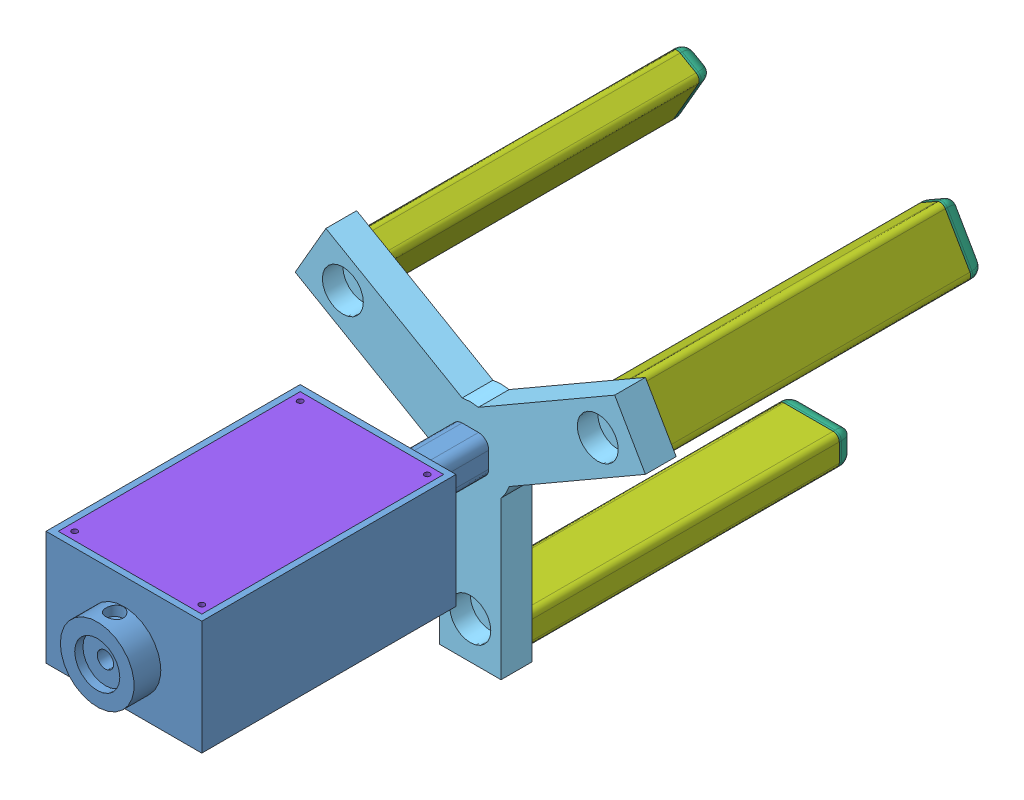
SolidWorks assembly NewGrapperWithServos, configuration Default. Lengths in mm.
Overall size (170.88 147.99 355).
26 component instances, 9 part files, 17 mates.
Components (placement in the parent):
- ServoHolder-1: ServoHolder [Default] at (20.6091 41.5283 66.4389) size (76 55.75 187)
- ServoWithHornCover-1: ServoWithHornCover [Default] at (-47.2507 32.9202 59.0729) x (0 0 -1) z (1 0 0) size (60.01 49.75 41.52) (flexible)
  - MG996R-1: MG996R [Default] at (22.884 11.6081 50.6098) size (53.5 42.75 19.5)
  - ServoHornWithGroove-1: ServoHornWithGroove [Default] at (12.384 56.3581 50.6098) x (0.653288 0 0.75711) z (0.75711 0 -0.653288) size (30 9.5 30)
  - ServoCover-1: ServoCover [Default] at (34.0772 41.3581 67.8598) x (-1 0 0) z (0 0 -1) size (57.5 20 34.5)
- ServoWithHornCover-2: ServoWithHornCover [Default] at (-12.7507 32.9202 59.0729) x (0 0 -1) z (1 0 0) size (60.01 49.75 41.52) (flexible)
  - MG996R-1: MG996R [Default] at (22.884 11.6081 50.6098) size (53.5 42.75 19.5)
  - ServoHornWithGroove-1: ServoHornWithGroove [Default] at (12.384 56.3581 50.6098) x (0.586538 0 0.809922) z (0.809922 0 -0.586538) size (30 9.5 30)
  - ServoCover-1: ServoCover [Default] at (34.0772 41.3581 67.8598) x (-1 0 0) z (0 0 -1) size (57.5 20 34.5)
- 3GripperAssembly-1: 3GripperAssembly [Default] at (-30.3334 -49.3942 19.9719) x (1 0 0) z (0 1 0) size (170.88 173 147.99)
  - EndEffector3Grapper-1: EndEffector3Grapper [Default] at (50.9425 60.533 115.9226) size (170.88 20 147.99)
  - FingerAssembly-1: FingerAssembly [Default] at (105.0348 198.5242 138.6511) x (-0.5 0 0.866025) z (0 1 0) size (30 15 158)
    - FingerTip-1: FingerTip [Default] at (7.3627 17.1904 24.0088) size (30 15 11)
    - Finger-1: Finger [Default] at (7.3627 18.2904 -122.9912) x (1 0 0) z (0 -1 0) size (30 150 15)
  - FingerAssembly-2: FingerAssembly [Default] at (4.2129 198.5242 151.4036) x (-0.5 0 -0.866025) z (0 1 0) size (30 15 158)
    - FingerTip-1: FingerTip [Default] at (7.3627 17.1904 24.0088) size (30 15 11)
    - Finger-1: Finger [Default] at (7.3627 18.2904 -122.9912) x (1 0 0) z (0 -1 0) size (30 150 15)
  - FingerAssembly-3: FingerAssembly [Default] at (43.5799 198.5242 57.713) x (1 0 0) z (0 1 0) size (30 15 158)
    - FingerTip-1: FingerTip [Default] at (7.3627 17.1904 24.0088) size (30 15 11)
    - Finger-1: Finger [Default] at (7.3627 18.2904 -122.9912) x (1 0 0) z (0 -1 0) size (30 150 15)
- ServoWithHornCover-4: ServoWithHornCover [Default] at (-30.0007 32.9202 119.5729) x (0 0 -1) z (1 0 0) size (60.01 49.75 41.52)
  - MG996R-1: MG996R [Default] at (22.884 11.6081 50.6098) size (53.5 42.75 19.5)
  - ServoHornWithGroove-1: ServoHornWithGroove [Default] at (12.384 56.3581 50.6098) x (-0.837169 0 -0.546944) z (-0.546944 0 0.837169) size (30 9.5 30)
  - ServoCover-1: ServoCover [Default] at (34.0772 41.3581 67.8598) x (-1 0 0) z (0 0 -1) size (57.5 20 34.5)
- ServoHolderCover-1: ServoHolderCover [Default] at (20.6091 94.2783 66.4389) x (0 0 -1) z (1 0 0) size (118 3 70)
- socket head cap screw_iso-1: socket head cap screw_iso [ISO 4762 M6 x 20 - 20S] at (20.6091 66.5283 -55.5611) x (0 0 1) z (-0.923728 -0.383049 0) size (26 10 10)
Mates (geometry in assembly coordinates):
- Coincident11: coincident anti-aligned: plane of ServoHolder-1 through (-6.3909 85.2783 15.9389) normal (1 0 0); plane of ServoWithHornCover-1/MG996R-1 through (-6.3909 80.2783 56.4389) normal (-1 0 0)
- Coincident13: coincident anti-aligned: plane of ServoWithHornCover-1/ServoCover-1 through (20.6091 74.2783 24.9957) normal (1 0 0); plane of ServoWithHornCover-2/ServoCover-1 through (20.6091 74.2783 24.9957) normal (-1 0 0)
- Coincident14: coincident aligned: plane of ServoWithHornCover-1/ServoCover-1 through (-13.8909 94.2783 58.4389) normal (0 1 0); plane of ServoWithHornCover-2/ServoCover-1 through (20.6091 94.2783 58.4389) normal (0 1 0)
- Coincident15: coincident aligned: plane of ServoWithHornCover-1/ServoCover-1 through (-13.8909 94.2783 13.9389) normal (0 0 -1); plane of ServoWithHornCover-2/ServoCover-1 through (20.6091 94.2783 13.9389) normal (0 0 -1)
- Coincident16: coincident anti-aligned: plane of ServoHolder-1 through (20.6091 44.5283 66.4389) normal (0 1 0); plane of ServoWithHornCover-1/MG996R-1 through (3.3591 44.5283 36.1889) normal (0 -1 0)
- Coincident17: coincident aligned: plane of ServoHolder-1 through (13.1091 85.2783 15.9389) normal (0 0 -1); plane of ServoWithHornCover-1/MG996R-1 through (13.1091 80.2783 15.9389) normal (0 0 -1)
- Coincident20: coincident anti-aligned: plane of ServoHolder-1 through (30.3591 85.2783 76.4389) normal (-1 0 0); plane of ServoWithHornCover-4/MG996R-1 through (30.3591 80.2783 116.9389) normal (1 0 0)
- Coincident21: coincident anti-aligned: plane of ServoHolder-1 through (20.6091 44.5283 66.4389) normal (0 1 0); plane of ServoWithHornCover-4/MG996R-1 through (20.6091 44.5283 96.6889) normal (0 -1 0)
- Coincident22: coincident anti-aligned: plane of ServoHolder-1 through (58.6111 71.7783 116.9389) normal (0 0 -1); plane of ServoWithHornCover-4/MG996R-1 through (30.3591 80.2783 116.9389) normal (0 0 1)
- Coincident24: coincident anti-aligned: plane of ServoHolder-1 through (20.6091 94.2783 66.4389) normal (0 1 0); plane of ServoHolderCover-1 through (20.6091 94.2783 66.4389) normal (0 -1 0)
- Coincident25: coincident anti-aligned: plane of ServoHolder-1 through (55.6091 97.2783 7.4389) normal (-1 0 0); plane of ServoHolderCover-1 through (55.6091 97.2783 125.4389) normal (1 0 0)
- Coincident26: coincident anti-aligned: plane of ServoHolder-1 through (-14.3909 97.2783 7.4389) normal (0 0 1); plane of ServoHolderCover-1 through (55.6091 97.2783 7.4389) normal (0 0 -1)
- Coincident27: coincident anti-aligned: plane of ServoHolder-1 through (29.6091 75.5283 -45.5611) normal (0 1 0); plane of 3GripperAssembly-1/EndEffector3Grapper-1 through (11.6091 75.5283 -45.5611) normal (0 -1 0)
- Coincident28: coincident anti-aligned: plane of ServoHolder-1 through (11.6091 57.5283 -45.5611) normal (-1 0 0); plane of 3GripperAssembly-1/EndEffector3Grapper-1 through (11.6091 57.5283 -45.5611) normal (1 0 0)
- Coincident29: coincident anti-aligned: plane of ServoHolder-1 through (20.6091 41.5283 -45.5611) normal (0 0 -1); plane of 3GripperAssembly-1/EndEffector3Grapper-1 through (20.6091 66.5283 -45.5611) normal (0 0 1)
- Coincident30: coincident aligned: plane of 3GripperAssembly-1/EndEffector3Grapper-1 through (20.6091 66.5283 -55.5611) normal (0 0 -1); plane of socket head cap screw_iso-1 through (20.6091 66.5283 -55.5611) normal (0 0 -1)
- Concentric1: concentric aligned: cylinder of 3GripperAssembly-1/EndEffector3Grapper-1 through (20.6091 66.5283 -50.5611) axis (0 0 -1) radius 5; cylinder of socket head cap screw_iso-1 through (20.6091 66.5283 -87.3111) axis (0 0 -1) radius 5
